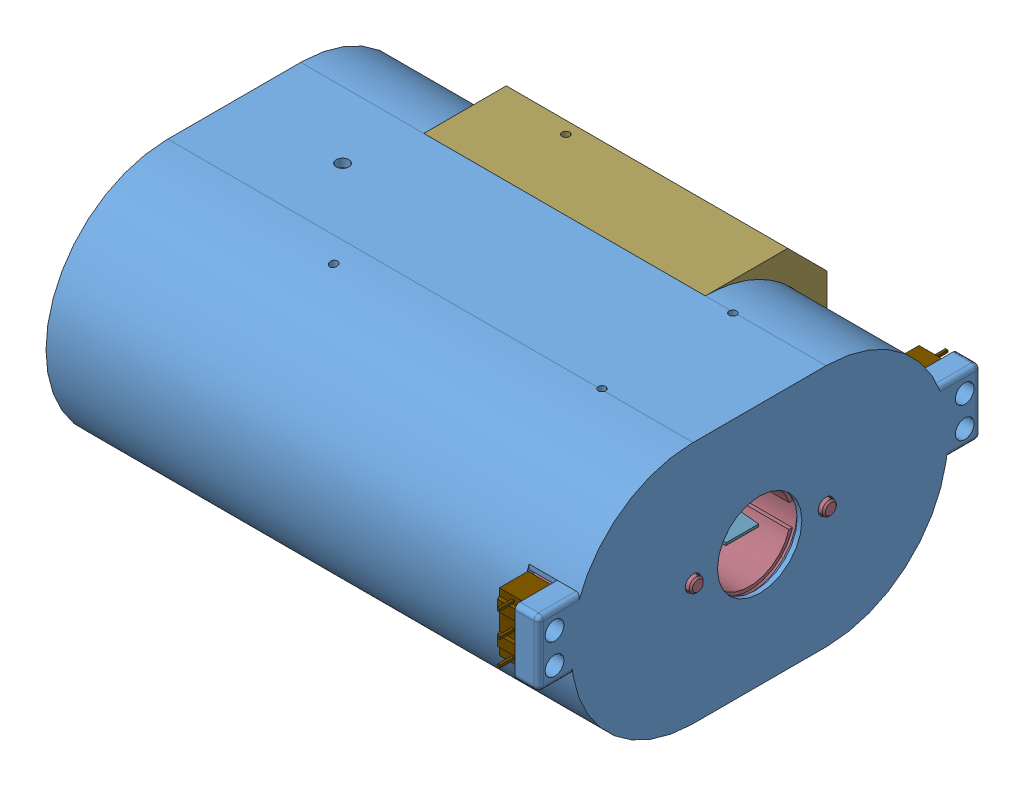
SolidWorks assembly EnsamblajeRectificado, configuration Default. Lengths in mm.
Overall size (113 51.95 95.45).
22 component instances, 19 part files, 64 mates.
Components (placement in the parent):
- Base2Rectificado-1: Base2Rectificado [Default] at (1.8051 0 -0.4031) size (112 51.95 94.25)
- Engranaje2Rectificado-1: Engranaje2Rectificado [Default] at (-79.1949 13.4849 -9.2874) x (1 0 0) z (0 0.998281 -0.05861) size (8.9 19.83 19.98)
- Engranaje2XLRectificado-1: Engranaje2XLRectificado [Default] at (-79.1949 13.4849 8.8741) x (1 0 0) z (0 -0.152721 0.988269) size (9 19.83 19.98)
- Servo SG90Rectificado-1: Servo SG90Rectificado [Valor predeterminado] at (-91.1949 13.4849 -4.0374) x (0 0 1) z (0 1 0) size (32 29 12)
- Servo SG90Rectificado-2: Servo SG90Rectificado [Valor predeterminado] at (-87.3949 1.5 18.7669) x (0 1 0) z (-1 0 0) size (32 29 12)
- SostieneEjes2SuavizadoRectificado-2: SostieneEjes2SuavizadoRectificado [Default] at (-79.3949 0 -0.4031) x (0 0 1) z (-1 0 0) size (75.39 47.49 14)
- PortaCadenaaRectificado-3: PortaCadenaaRectificado [Default] at (-81.4949 0 -0.4031) x (0 0 1) z (0 -1 0) size (45 38 15.95)
- TapaPortaCadenaRectificado-1: TapaPortaCadenaRectificado [Default] at (-81.4949 -1.5 -0.4031) x (0 0 1) z (0 -1 0) size (45 37.5 2)
- FijadorPortaCadenaRectificado-1: FijadorPortaCadenaRectificado [Default] at (-81.2697 -2.5 -16.5617) x (0 0 1) z (0 -1 0) size (26.62 17.25 11)
- SostieneEjesParte2Rectificado-1: SostieneEjesParte2Rectificado [Default] at (-68.8949 0 -0.4031) x (0 0 1) z (-1 0 0) size (75.54 47.49 10.5)
- NewChainRammerGearRectificado-1: NewChainRammerGearRectificado [Default] at (-87.3949 -3.75 3.7469) x (-0.405066 -0.914287 0) z (0 0 -1) size (11.5 11.5 8.52)
- CadenaMasGrandeRectificado-1: CadenaMasGrandeRectificado [Default] at (-89.1244 2.505 2.0969) x (0 -1 0) z (0 0 -1) size (5 7.23 5.5)
- ArduinoEsquemaRectificado-1: ArduinoEsquemaRectificado [Default] at (-47.6532 25.95 -5.5031) x (1 0 0) z (0 1 0) size (68.6 53.3 1.75) (hidden)
- BotoneraRectificado-1: BotoneraRectificado [Default] at (-21.9532 0 -14.5791) x (0 0 1) z (-1 0 0) size (25.95 25.95 60)
- PortaPortaherramientasRectificada-1: PortaPortaherramientasRectificada [Default] at (1.6051 0 13.773) x (1 0 0) z (0 -0.999998 0.001991) size (86.05 47.32 19.05)
- PortaPortaherramientasRectificada-2: PortaPortaherramientasRectificada [Default] at (1.6051 0 -14.5791) x (1 0 0) z (0 0.001991 -0.999998) size (86.05 47.32 19.05)
- DestornilladorRectificado-1: DestornilladorRectificado [Default] at (-65.8949 -0.0282 -0.403) x (0 -0.001991 -0.999998) z (1 0 0) size (18.48 17.08 66)
- TenedorRectificado-1: TenedorRectificado [Default] at (-65.8949 14.176 -14.5509) x (0 -0.999998 -0.001991) z (1 0 0) size (18.48 17.08 66)
- WrenchRectificado-1: WrenchRectificado [Default] at (-65.8949 -14.176 -14.6073) x (0 0.999998 0.001991) z (1 0 0) size (18.48 17.08 66)
- SostieneDestornillador-1: SostieneDestornillador [Default] at (-65.8949 0.0282 27.949) x (0 -0.001991 -0.999998) z (1 0 0) size (18.48 17.08 25)
- FinalDeCarrera-1: FinalDeCarrera [Default] at (-4.0699 2.7805 -45.1291) x (0 -1 0) z (-1 0 0) size (12.5 11.7 5.75)
- FinalDeCarrera-2: FinalDeCarrera [Default] at (-4.0699 2.7805 44.323) x (0 -1 0) z (1 0 0) size (12.5 11.7 5.75)
Mates (geometry in assembly coordinates):
- Parallel1: parallel anti-aligned: plane of Base2Rectificado-1 through (-108.1949 24.2 -0.4031) normal (0 -1 0); plane of SostieneEjes2SuavizadoRectificado-2 through (-81.3949 23.7456 -0.4031) normal (0 1 0)
- Concentric7: concentric aligned: cylinder of Engranaje2XLRectificado-1 through (-70.1949 13.4849 8.8741) axis (-1 0 0) radius 1; cylinder of SostieneEjes2SuavizadoRectificado-2 through (-70.6949 13.4849 8.8741) axis (-1 0 0) radius 1.1
- Concentric8: concentric aligned: cylinder of Engranaje2Rectificado-1 through (-70.2949 13.4849 -9.2874) axis (-1 0 0) radius 1; cylinder of Servo SG90Rectificado-1 through (-78.1949 13.4849 -9.2874) axis (-1 0 0) radius 2.25
- Distance5: distance = 0.2 mm anti-aligned: plane of Engranaje2XLRectificado-1 through (-79.1949 13.4849 8.8741) normal (-1 0 0); plane of SostieneEjes2SuavizadoRectificado-2 through (-79.3949 0 -0.4031) normal (1 0 0)
- Concentric9: concentric anti-aligned: cylinder of Servo SG90Rectificado-1 through (-89.1949 13.4849 9.5876) axis (-1 0 0) radius 1; cylinder of SostieneEjes2SuavizadoRectificado-2 through (-89.1949 13.4849 9.5876) axis (1 0 0) radius 0.9
- Concentric10: concentric anti-aligned: cylinder of Servo SG90Rectificado-1 through (-89.1949 13.4849 -17.6624) axis (-1 0 0) radius 1; cylinder of SostieneEjes2SuavizadoRectificado-2 through (-89.1949 13.4849 -17.6624) axis (1 0 0) radius 0.9
- Coincident10: coincident anti-aligned: plane of Servo SG90Rectificado-1 through (-89.1949 13.4849 -17.6624) normal (1 0 0); plane of SostieneEjes2SuavizadoRectificado-2 through (-89.1949 0 -0.4031) normal (-1 0 0)
- Distance8: distance = 1 mm anti-aligned: plane of Servo SG90Rectificado-1 through (-78.1949 13.4849 -9.2874) normal (1 0 0); plane of Engranaje2Rectificado-1 through (-77.1949 13.4849 -9.2874) normal (-1 0 0)
- Distance6: distance = 0.1 mm anti-aligned: plane of PortaCadenaaRectificado-3 through (-81.4949 -1.5 7.1881) normal (1 0 0); plane of SostieneEjes2SuavizadoRectificado-2 through (-81.3949 0 -0.4031) normal (-1 0 0)
- Concentric12: concentric anti-aligned: cylinder of Base2Rectificado-1 through (-108.1949 0 -0.4031) axis (1 0 0) radius 9; cylinder of SostieneEjes2SuavizadoRectificado-2 through (-79.3949 0 -0.4031) axis (-1 0 0) radius 7.7411
- Concentric13: concentric aligned: cylinder of SostieneEjes2SuavizadoRectificado-2 through (-79.3949 0 -0.4031) axis (-1 0 0) radius 7.7411; cylinder of PortaCadenaaRectificado-3 through (-68.9949 0 -0.4031) axis (-1 0 0) radius 7.5911
- Parallel3: parallel aligned: plane of SostieneEjes2SuavizadoRectificado-2 through (-81.3949 23.7456 -0.4031) normal (0 1 0); plane of PortaCadenaaRectificado-3 through (-94.4949 6 -5.3119) normal (0 1 0)
- Coincident22: coincident anti-aligned: plane of Servo SG90Rectificado-2 through (-81.3949 -9.75 34.7669) normal (1 0 0); plane of SostieneEjes2SuavizadoRectificado-2 through (-81.3949 0 -0.4031) normal (-1 0 0)
- Concentric16: concentric aligned: cylinder of PortaCadenaaRectificado-3 through (-94.4949 -1.5 -5.3119) axis (0 1 0) radius 12.5; cylinder of TapaPortaCadenaRectificado-1 through (-94.4949 -2.5 -5.3119) axis (0 1 0) radius 12.5
- Concentric17: concentric aligned: cylinder of PortaCadenaaRectificado-3 through (-94.4949 -1.5 -25.3119) axis (0 1 0) radius 12.5; cylinder of TapaPortaCadenaRectificado-1 through (-94.4949 -2.5 -25.3119) axis (0 1 0) radius 12.5
- Coincident24: coincident anti-aligned: plane of PortaCadenaaRectificado-3 through (-94.4949 -1.5 -5.3119) normal (0 -1 0); plane of TapaPortaCadenaRectificado-1 through (-81.4949 -1.5 -0.4031) normal (0 1 0)
- Concentric18: concentric anti-aligned: cylinder of TapaPortaCadenaRectificado-1 through (-91.9949 -1.5 -24.0619) axis (0 -1 0) radius 1; cylinder of FijadorPortaCadenaRectificado-1 through (-91.9949 -4.5 -24.0619) axis (0 1 0) radius 1.25
- Concentric19: concentric anti-aligned: cylinder of TapaPortaCadenaRectificado-1 through (-91.9949 -1.5 -9.0619) axis (0 -1 0) radius 1; cylinder of FijadorPortaCadenaRectificado-1 through (-91.9949 -4.5 -9.0619) axis (0 1 0) radius 1.25
- Coincident25: coincident anti-aligned: plane of TapaPortaCadenaRectificado-1 through (-81.4949 -2.5 -0.4031) normal (0 -1 0); plane of FijadorPortaCadenaRectificado-1 through (-90.1771 -2.5 -8.2519) normal (0 1 0)
- Coincident28: coincident anti-aligned: plane of SostieneEjes2SuavizadoRectificado-2 through (-79.3949 0 -0.4031) normal (1 0 0); plane of SostieneEjesParte2Rectificado-1 through (-79.3949 0 -0.4031) normal (-1 0 0)
- Concentric37: concentric aligned: cylinder of SostieneEjes2SuavizadoRectificado-2 through (-81.3949 0 13.6237) axis (1 0 0) radius 23.7456; cylinder of SostieneEjesParte2Rectificado-1 through (-69.8949 0 13.6237) axis (1 0 0) radius 23.7456
- Concentric38: concentric aligned: cylinder of SostieneEjes2SuavizadoRectificado-2 through (-81.3949 0 -14.4298) axis (1 0 0) radius 23.7456; cylinder of SostieneEjesParte2Rectificado-1 through (-69.8949 0 -14.4298) axis (1 0 0) radius 23.7456
- Distance9: distance = 0.1 mm anti-aligned: plane of CadenaMasGrandeRectificado-1 through (-89.1244 2.505 -3.4031) normal (0 0 -1); plane of PortaCadenaaRectificado-3 through (-81.4949 -7.5911 -3.5031) normal (0 0 1)
- Distance10: distance = 0.25 mm anti-aligned: plane of CadenaMasGrandeRectificado-1 through (-85.5115 4.75 -3.4031) normal (0 1 0); plane of PortaCadenaaRectificado-3 through (-81.4949 5 -0.4031) normal (0 -1 0)
- Coincident31: coincident anti-aligned: plane of Base2Rectificado-1 through (1.8051 0 -0.4031) normal (1 0 0); plane of ? through (1.8051 -0.1 -9.7709) normal (-1 0 0)
- Coincident34: coincident anti-aligned: plane of Base2Rectificado-1 through (1.8051 0 -0.4031) normal (1 0 0); plane of ? through (1.8051 -0.1 8.9648) normal (-1 0 0)
- Distance12: distance = 0.1 mm anti-aligned: plane of ? through (-11.1949 26.05 10.3398) normal (0 -1 0); plane of Base2Rectificado-1 through (-108.1949 25.95 -0.4031) normal (0 1 0)
- Coincident35: coincident aligned: plane of ? through (3.8051 28.5 10.3398) normal (0 1 0); plane of ? through (3.8051 28.5 -8.3959) normal (0 1 0)
- Distance13: distance = 0.2 mm anti-aligned: plane of Base2Rectificado-1 through (-108.1949 0 -11.3459) normal (0 0 1); plane of ? through (3.8051 -28.7 -11.1459) normal (0 0 -1)
- Distance14: distance = 0.2 mm anti-aligned: plane of ? through (3.8051 -28.7 10.3398) normal (0 0 1); plane of Base2Rectificado-1 through (-108.1949 0 10.5398) normal (0 0 -1)
- Concentric40: concentric anti-aligned: cylinder of Servo SG90Rectificado-2 through (-87.3949 -3.75 5.7669) axis (0 0 1) radius 2.25; cylinder of NewChainRammerGearRectificado-1 through (-87.3949 -3.75 5.7669) axis (0 0 -1) radius 5.75
- Concentric44: concentric aligned: cylinder of Servo SG90Rectificado-2 through (-87.3949 -12.125 16.7669) axis (0 0 1) radius 1; cylinder of SostieneEjes2SuavizadoRectificado-2 through (-87.3949 -12.125 10.7669) axis (0 0 1) radius 0.9
- Coincident40: coincident anti-aligned: plane of Servo SG90Rectificado-2 through (-87.3949 -12.125 16.7669) normal (0 0 -1); plane of SostieneEjes2SuavizadoRectificado-2 through (-93.3949 -17.485 16.7669) normal (0 0 1)
- Coincident41: coincident anti-aligned: plane of Servo SG90Rectificado-2 through (-87.3949 -3.75 5.7669) normal (0 0 -1); plane of NewChainRammerGearRectificado-1 through (-87.3949 -3.75 5.7669) normal (0 0 1)
- Coincident42: coincident anti-aligned: plane of Base2Rectificado-1 through (-108.1949 25.95 -0.4031) normal (0 1 0); plane of ArduinoEsquemaRectificado-1 through (-47.6532 25.95 -5.5031) normal (0 -1 0)
- Concentric48: concentric aligned: circle of Base2Rectificado-1; circle of ArduinoEsquemaRectificado-1
- Concentric49: concentric aligned: circle of Base2Rectificado-1; circle of ArduinoEsquemaRectificado-1
- Concentric50: concentric aligned: cylinder of Base2Rectificado-1 through (-108.1949 0 -14.5791) axis (1 0 0) radius 25.95; cylinder of BotoneraRectificado-1 through (-81.9532 0 -14.5791) axis (1 0 0) radius 25.95
- Parallel10: parallel anti-aligned: plane of ArduinoEsquemaRectificado-1 through (-47.6532 25.95 -5.5031) normal (0 -1 0); plane of BotoneraRectificado-1 through (-81.9532 25.95 -40.5291) normal (0 1 0)
- Coincident44: coincident aligned: plane of ArduinoEsquemaRectificado-1 through (-81.9532 27.7 21.1469) normal (-1 0 0); plane of BotoneraRectificado-1 through (-81.9532 0 -14.5791) normal (-1 0 0)
- Concentric51: concentric aligned: cylinder of Base2Rectificado-1 through (3.8051 0 13.773) axis (-1 0 0) radius 1.7; cylinder of PortaPortaherramientasRectificada-1 through (4.8051 0 13.773) axis (-1 0 0) radius 1.5
- Concentric52: concentric aligned: cylinder of Base2Rectificado-1 through (3.8051 0 -14.5791) axis (-1 0 0) radius 1.7; cylinder of PortaPortaherramientasRectificada-2 through (4.8051 0 -14.5791) axis (-1 0 0) radius 1.5
- Distance15: distance = 0.2 mm anti-aligned: plane of PortaPortaherramientasRectificada-2 through (1.6051 0 -14.5791) normal (1 0 0); plane of Base2Rectificado-1 through (1.8051 0 -14.5791) normal (-1 0 0)
- Distance16: distance = 0.2 mm anti-aligned: plane of PortaPortaherramientasRectificada-1 through (1.6051 0 13.773) normal (1 0 0); plane of Base2Rectificado-1 through (1.8051 0 -14.5791) normal (-1 0 0)
- Concentric55: concentric aligned: cylinder of Base2Rectificado-1 through (-85.1027 15.95 -0.4031) axis (0 1 0) radius 1.35; cylinder of SostieneEjes2SuavizadoRectificado-2 through (-85.1027 13.7456 -0.4031) axis (0 1 0) radius 0.9
- Concentric56: concentric aligned: cylinder of Base2Rectificado-1 through (-85.1027 -30.6714 33.0393) axis (0 0.844938 -0.534864) radius 1.35; cylinder of SostieneEjes2SuavizadoRectificado-2 through (-85.1027 -27.6837 31.148) axis (0 0.844938 -0.534864) radius 0.9
- Concentric57: concentric aligned: cylinder of Base2Rectificado-1 through (-85.1027 -28.0923 -40.4629) axis (0 0.733478 0.679713) radius 1.35; cylinder of SostieneEjes2SuavizadoRectificado-2 through (-85.1027 -20.6109 -33.5298) axis (0 0.733478 0.679713) radius 0.9
- GearMate4: gear = 20 : 12.6355 mm: cylinder of PortaPortaherramientasRectificada-2 through (-79.1949 0 -14.5791) axis (1 0 0) radius 6.3177; cylinder of Engranaje2Rectificado-1 through (-70.2949 13.4849 -9.2874) axis (-1 0 0) radius 10
- GearMate5: gear = 20 : 12.6355 mm: cylinder of PortaPortaherramientasRectificada-1 through (-79.1949 0 13.773) axis (1 0 0) radius 6.3177; cylinder of Engranaje2XLRectificado-1 through (-70.1949 13.4849 8.8741) axis (-1 0 0) radius 10
- GearMate2: gear = 20 : 20 mm: cylinder of Engranaje2Rectificado-1 through (-70.2949 13.4849 -9.2874) axis (-1 0 0) radius 10; cylinder of Engranaje2XLRectificado-1 through (-70.1949 13.4849 8.8741) axis (-1 0 0) radius 10
- Concentric59: concentric anti-aligned: cylinder of PortaPortaherramientasRectificada-2 through (-68.3949 14.176 -14.5509) axis (1 0 0) radius 8.8229; cylinder of TenedorRectificado-1 through (-55.8949 14.176 -14.5509) axis (-1 0 0) radius 8.5411
- Parallel15: parallel anti-aligned: plane of PortaPortaherramientasRectificada-2 through (-71.0779 -0.005 -12.0791) normal (0 0.001991 -0.999998); plane of TenedorRectificado-1 through (-57.8949 5.9321 -12.3173) normal (0 -0.001991 0.999998)
- Concentric60: concentric anti-aligned: cylinder of PortaPortaherramientasRectificada-2 through (-68.3949 -14.176 -14.6073) axis (1 0 0) radius 8.7411; cylinder of WrenchRectificado-1 through (0.1051 -14.176 -14.6073) axis (-1 0 0) radius 8.5411
- Parallel16: parallel anti-aligned: plane of PortaPortaherramientasRectificada-2 through (-71.0779 0.005 -17.0791) normal (0 -0.001991 0.999998); plane of WrenchRectificado-1 through (0.1051 -14.168 -18.6073) normal (0 0.001991 -0.999998)
- Concentric61: concentric anti-aligned: cylinder of PortaPortaherramientasRectificada-1 through (-68.3949 -0.0282 -0.403) axis (1 0 0) radius 8.8229; cylinder of DestornilladorRectificado-1 through (-55.8949 -0.0282 -0.403) axis (-1 0 0) radius 8.5411
- Parallel17: parallel aligned: plane of PortaPortaherramientasRectificada-1 through (-71.0779 -2.5 13.7779) normal (0 0.999998 -0.001991); plane of DestornilladorRectificado-1 through (-57.8949 2.2034 -9.6486) normal (0 0.999998 -0.001991)
- Parallel18: parallel anti-aligned: plane of PortaPortaherramientasRectificada-1 through (-71.0779 0.0093 18.4579) normal (0 0.001991 0.999998); plane of SostieneDestornillador-1 through (-40.8949 -1.2402 18.7104) normal (0 -0.001991 -0.999998)
- Concentric62: concentric anti-aligned: cylinder of PortaPortaherramientasRectificada-1 through (-68.3949 0.0282 27.949) axis (1 0 0) radius 8.7411; cylinder of SostieneDestornillador-1 through (-40.8949 0.0282 27.949) axis (-1 0 0) radius 8.5411
- Coincident45: coincident anti-aligned: plane of Base2Rectificado-1 through (-1.1949 -10 -38.5291) normal (-1 0 0); plane of FinalDeCarrera-1 through (-1.1949 9.0305 -39.0291) normal (1 0 0)
- Distance17: distance = 0.5 mm anti-aligned: plane of FinalDeCarrera-1 through (-4.0699 2.7805 -39.0291) normal (0 0 1); plane of Base2Rectificado-1 through (1.8051 0 -38.5291) normal (0 0 -1)
- Coincident48: coincident: line of Base2Rectificado-1 through (-1.1949 -3.4695 -38.5291) axis (-1 0 0); plane of FinalDeCarrera-1 through (-6.9449 -3.4695 -39.0291) normal (0 -1 0)
- Coincident49: coincident anti-aligned: plane of Base2Rectificado-1 through (-1.1949 -10 37.723) normal (-1 0 0); plane of FinalDeCarrera-2 through (-1.1949 9.0305 38.223) normal (1 0 0)
- Concentric63: concentric anti-aligned: cylinder of Base2Rectificado-1 through (3.8051 6.0305 43.323) axis (-1 0 0) radius 2; cylinder of FinalDeCarrera-2 through (-6.945 6.0305 43.323) axis (1 0 0) radius 1
- Concentric64: concentric anti-aligned: cylinder of Base2Rectificado-1 through (3.8051 -0.4695 43.323) axis (-1 0 0) radius 2; cylinder of FinalDeCarrera-2 through (-6.945 -0.4695 43.323) axis (1 0 0) radius 1
